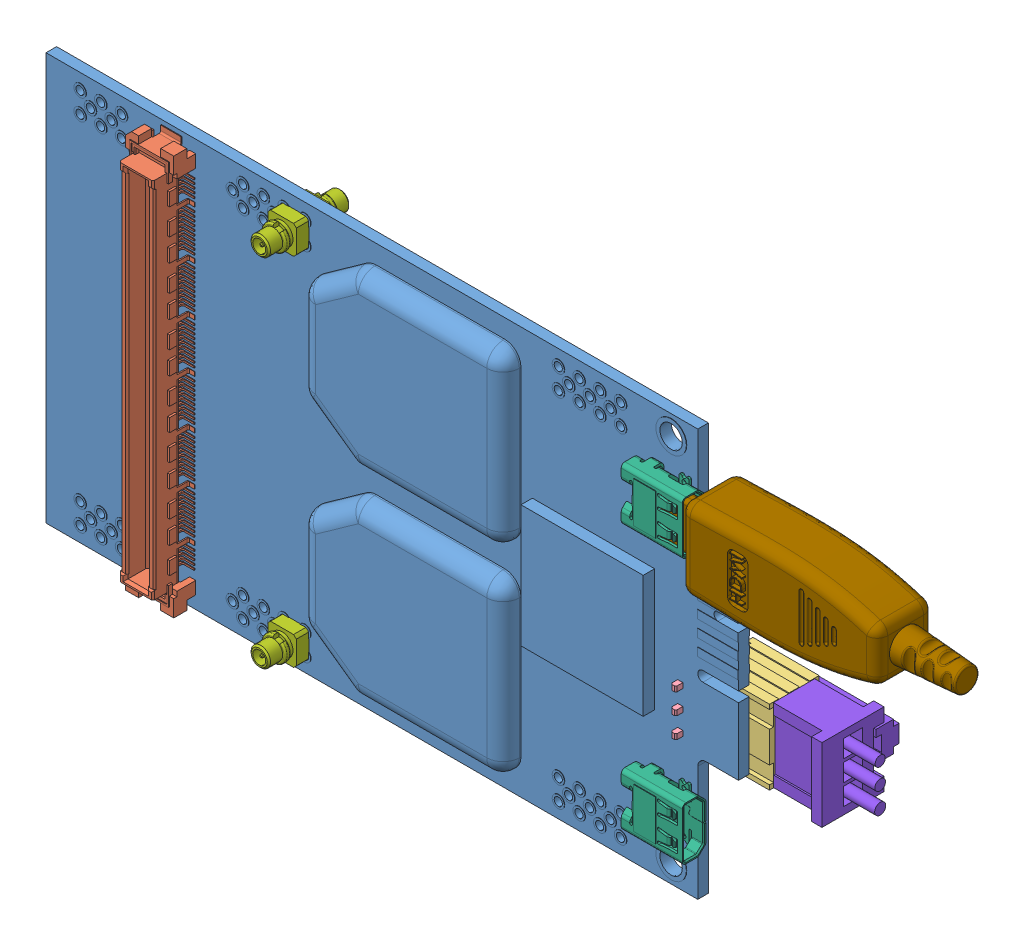
SolidWorks assembly VMM3Hybrid_Reworked, configuration Default. Lengths in mm.
Overall size (114.42 50 15.64).
14 component instances, 9 part files, 32 mates.
Components (placement in the parent):
- VMM3Module_REWork-1: VMM3Module_REWork [Default] at origin size (85 50 4.5)
- fx10a-140p_14-sv1_71_-1: fx10a-140p_14-sv1_71_ [Default] at (14.069 27.75 2.1922) x (-1 0 0) z (0 0 1) size (5.9 49.1 5.1)
- IPL1-103-01-L-S-RA-K-1: IPL1-103-01-L-S-RA-K [Default] at (79.372 19.275 -3.048) x (0 1 0) z (0 0 -1) size (10.02 9.97 10.02)
  - IPL1-103-01-S-RA-K_HDR-1: IPL1-103-01-S-RA-K_HDR [Default] at origin size (9.14 8.13 6.6)
  - T-1S64-01-03-L-S-RA-1: T-1S64-01-03-L-S-RA [Default] at origin size (5.71 3.11 5.27)
  - T-1S64-01-03-L-S-RA2-1: T-1S64-01-03-L-S-RA2 [Default] at origin size (5.71 6.48 0.63)
- MicroHDMI-1: MicroHDMI [Default] at (81.8 36.25 1.35) x (0 1 0) z (1 0 0) size (6.5 2.97 7.51)
- MMCX-P-P-H-ST-MT1-1: MMCX-P-P-H-ST-MT1 [Default] at (30.52 46.85 0.3) x (1 0 0) z (0 -1 0) size (3.5 5.9 3.5)
- MMCX-P-P-H-ST-MT1-2: MMCX-P-P-H-ST-MT1 [Default] at (30.52 3.15 0.3) x (1 0 0) z (0 -1 0) size (3.5 5.9 3.5)
- MMCX-P-P-H-ST-MT1-3: MMCX-P-P-H-ST-MT1 [Default] at (30.52 3.15 1) x (-1 0 0) z (0 -1 0) size (3.5 5.9 3.5)
- MMCX-P-P-H-ST-MT1-4: MMCX-P-P-H-ST-MT1 [Default] at (30.52 46.85 1) x (-1 0 0) z (0 -1 0) size (3.5 5.9 3.5)
- MicroHDMI-2: MicroHDMI [Default] at (81.8 3.75 1.35) x (0 1 0) z (1 0 0) size (6.5 2.97 7.51)
- IPD1-03-S-K-1: IPD1-03-S-K [Default] at (94.739 19.275 -3.0099) x (0 -1 0) z (0 0 -1) size (9.02 16.38 10.24)
- Micro_HDMI_Connector-1: Micro_HDMI_Connector [Default] at (82.65 41.215 2.7) x (0 -1 0) z (-1 0 0) size (11.47 7 37.57)
Mates (geometry in assembly coordinates):
- Concentric1: concentric anti-aligned: circle of VMM3Module_REWork-1; circle of fx10a-140p_14-sv1_71_-1
- Coincident1: coincident anti-aligned: plane of VMM3Module_REWork-1 through (0 0 1.3) normal (0 0 1); plane of fx10a-140p_14-sv1_71_-1 through (16.0907 2.7267 1.3) normal (0 0 -1)
- Parallel1: parallel aligned: plane of VMM3Module_REWork-1 through (0 0 1.3) normal (-1 0 0); plane of fx10a-140p_14-sv1_71_-1 through (13.328 46.9 4) normal (-1 0 0)
- Concentric2: concentric anti-aligned: cylinder of VMM3Module_REWork-1 through (30.52 46.85 -9.7) axis (0 0 1) radius 0.5; cylinder of MMCX-P-P-H-ST-MT1-1 through (30.52 46.85 0.3) axis (0 0 -1) radius 1.19
- Coincident3: coincident anti-aligned: plane of VMM3Module_REWork-1 through (0 0 1.3) normal (0 0 1); plane of MMCX-P-P-H-ST-MT1-1 through (28.77 48.6 1.3) normal (0 0 -1)
- Parallel2: parallel aligned: plane of VMM3Module_REWork-1 through (0 0 1.3) normal (-1 0 0); plane of MMCX-P-P-H-ST-MT1-1 through (28.77 45.4358 0.3) normal (-1 0 0)
- Concentric3: concentric anti-aligned: cylinder of MMCX-P-P-H-ST-MT1-2 through (30.52 3.15 0.3) axis (0 0 -1) radius 1.19; cylinder of VMM3Module_REWork-1 through (30.52 3.15 -9.7) axis (0 0 1) radius 0.5
- Coincident5: coincident anti-aligned: plane of VMM3Module_REWork-1 through (0 0 1.3) normal (0 0 1); plane of MMCX-P-P-H-ST-MT1-2 through (28.77 4.9 1.3) normal (0 0 -1)
- Parallel3: parallel aligned: plane of MMCX-P-P-H-ST-MT1-1 through (28.77 45.4358 0.3) normal (-1 0 0); plane of MMCX-P-P-H-ST-MT1-2 through (28.77 1.7358 0.3) normal (-1 0 0)
- Coincident7: coincident anti-aligned: plane of VMM3Module_REWork-1 through (0 0 0) normal (0 0 -1); plane of MMCX-P-P-H-ST-MT1-4 through (32.27 48.6 0) normal (0 0 1)
- Concentric5: concentric aligned: cylinder of VMM3Module_REWork-1 through (30.52 46.85 -9.7) axis (0 0 1) radius 0.5; cylinder of MMCX-P-P-H-ST-MT1-4 through (30.52 46.85 1) axis (0 0 1) radius 1.19
- Parallel5: parallel aligned: plane of VMM3Module_REWork-1 through (0 0 1.3) normal (-1 0 0); plane of MMCX-P-P-H-ST-MT1-4 through (28.77 48.2642 1) normal (-1 0 0)
- Coincident9: coincident anti-aligned: plane of VMM3Module_REWork-1 through (0 0 0) normal (0 0 -1); plane of MMCX-P-P-H-ST-MT1-3 through (32.27 4.9 0) normal (0 0 1)
- Concentric6: concentric aligned: cylinder of MMCX-P-P-H-ST-MT1-3 through (30.52 3.15 1) axis (0 0 1) radius 1.19; cylinder of VMM3Module_REWork-1 through (30.52 3.15 -9.7) axis (0 0 1) radius 0.5
- Parallel6: parallel aligned: plane of VMM3Module_REWork-1 through (0 0 1.3) normal (-1 0 0); plane of MMCX-P-P-H-ST-MT1-3 through (28.77 4.5642 1) normal (-1 0 0)
- Coincident11: coincident anti-aligned: plane of VMM3Module_REWork-1 through (0 0 0) normal (0 0 -1); plane of IPL1-103-01-L-S-RA-K-1/IPL1-103-01-S-RA-K_HDR-1 through (79.372 14.703 0) normal (0 0 1)
- Parallel7: parallel aligned: plane of VMM3Module_REWork-1 through (85 23.4 -20.6781) normal (1 0 0); plane of IPL1-103-01-L-S-RA-K-1/IPL1-103-01-S-RA-K_HDR-1 through (87.5 14.703 -6.096) normal (1 0 0)
- Width1: width anti-aligned: plane of VMM3Module_REWork-1 through (80 15.15 -20.6781) normal (0 -1 0); plane of IPL1-103-01-L-S-RA-K-1/IPL1-103-01-S-RA-K_HDR-1 through (80.625 23.4 -20.6781) normal (0 1 0); plane of VMM3Module_REWork-1 through (79.372 23.847 -1.143) normal (0 1 0); plane of IPL1-103-01-L-S-RA-K-1/IPL1-103-01-S-RA-K_HDR-1 through (79.372 14.703 -6.096) normal (0 -1 0)
- Distance1: distance = 2.5 mm aligned: plane of IPL1-103-01-L-S-RA-K-1/IPL1-103-01-S-RA-K_HDR-1 through (87.5 14.703 -6.096) normal (1 0 0); plane of VMM3Module_REWork-1 through (85 23.4 -20.6781) normal (1 0 0)
- Coincident14: coincident anti-aligned: plane of VMM3Module_REWork-1 through (0 0 1.3) normal (0 0 1); plane of MicroHDMI-1 through (78.5375 40.1172 1.3) normal (0 0 -1)
- Parallel8: parallel aligned: plane of VMM3Module_REWork-1 through (80 0 1.3) normal (1 0 0); plane of MicroHDMI-1 through (81 38 1.3034) normal (1 0 0)
- Distance2: distance = 5.5 mm aligned: plane of MicroHDMI-1 through (74.65 44.5 1.95) normal (0 1 0); plane of VMM3Module_REWork-1 through (0 50 1.3) normal (0 1 0)
- Distance3: distance = 1 mm aligned: plane of MicroHDMI-1 through (81 38 1.3034) normal (1 0 0); plane of VMM3Module_REWork-1 through (80 0 1.3) normal (1 0 0)
- Coincident18: coincident anti-aligned: plane of VMM3Module_REWork-1 through (0 0 1.3) normal (0 0 1); plane of MicroHDMI-2 through (78.5375 7.6172 1.3) normal (0 0 -1)
- Distance4: distance = 5.5 mm aligned: plane of MicroHDMI-2 through (74.65 5.5 1.8) normal (0 -1 0); plane of VMM3Module_REWork-1 through (0 0 1.3) normal (0 -1 0)
- Distance5: distance = 1 mm aligned: plane of MicroHDMI-2 through (81 5.5 1.3034) normal (1 0 0); plane of VMM3Module_REWork-1 through (80 0 1.3) normal (1 0 0)
- Concentric7: concentric aligned: circle of IPL1-103-01-L-S-RA-K-1/IPL1-103-01-S-RA-K_HDR-1; circle of IPD1-03-S-K-1
- Coincident21: coincident anti-aligned: plane of IPL1-103-01-L-S-RA-K-1/IPL1-103-01-S-RA-K_HDR-1 through (87.5 14.703 -6.096) normal (1 0 0); plane of IPD1-03-S-K-1 through (87.5 14.7665 -0.4699) normal (-1 0 0)
- Parallel9: parallel aligned: plane of IPL1-103-01-L-S-RA-K-1/IPL1-103-01-S-RA-K_HDR-1 through (79.372 23.2755 0) normal (0 0 1); plane of IPD1-03-S-K-1 through (93.469 14.7665 -0.4699) normal (0 0 1)
- Coincident24: coincident anti-aligned: plane of MicroHDMI-1 through (77.45 48.15 1.6) normal (0 0 1); plane of Micro_HDMI_Connector-1 through (76.85 42.9229 1.6) normal (0 0 -1)
- Coincident25: coincident anti-aligned: plane of MicroHDMI-1 through (74.65 38.3 1.95) normal (0 1 0); plane of Micro_HDMI_Connector-1 through (76.85 38.3 2.8071) normal (0 -1 0)
- Coincident26: coincident anti-aligned: plane of MicroHDMI-1 through (76.85 40.54 2.235) normal (1 0 0); plane of Micro_HDMI_Connector-1 through (76.85 38.8 3.3) normal (-1 0 0)
